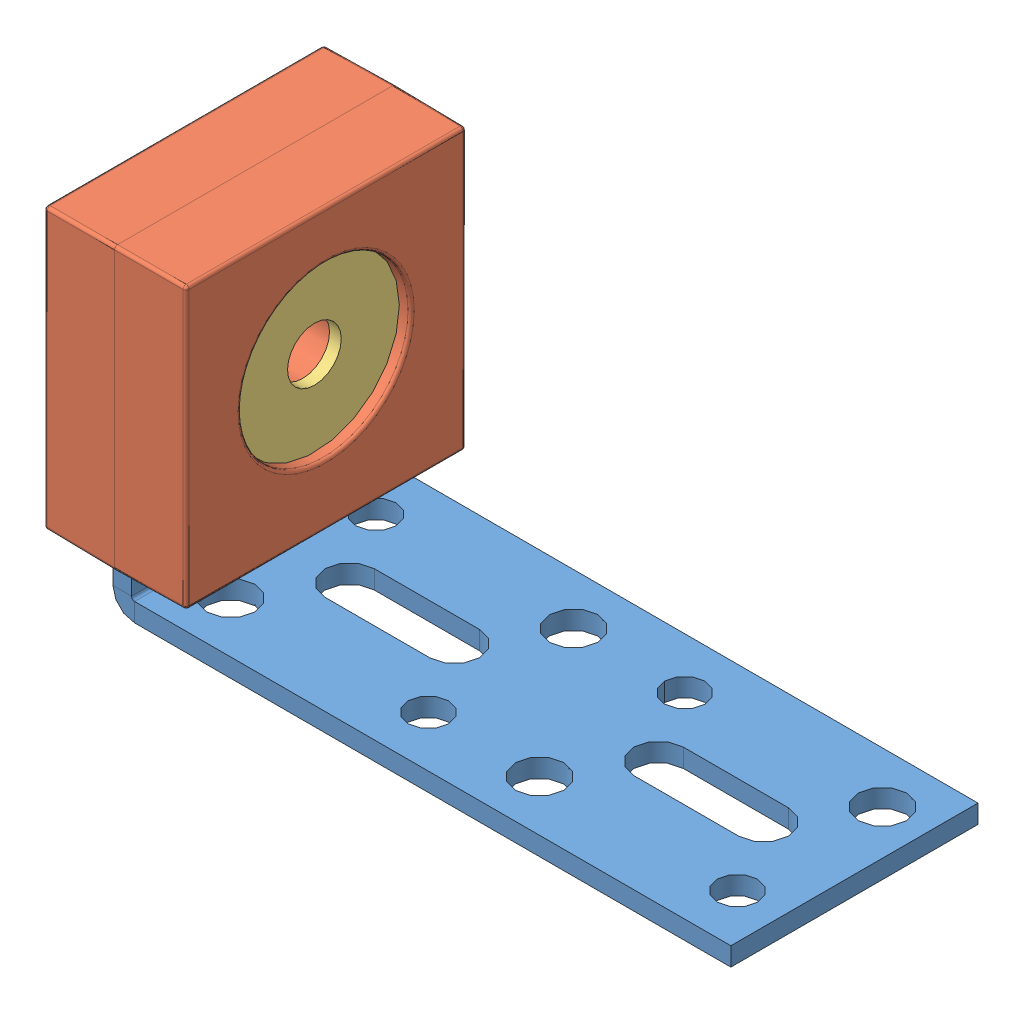
SolidWorks assembly 993684, configuration Default. Lengths in mm.
Overall size (108.5 53.9 45.5).
3 component instances, 3 part files, 5 mates.
Components (placement in the parent):
- 993684-1: 993684 [Default] at (-7.2845 29.1237 72.5984) size (100 50 40)
- 注塑-1: 注塑 [Default] at (-4.2845 60.0965 72.5984) size (23 45.5 45.5)
- 圆铁片-1: 圆铁片 [Default] at (3.4155 61.3237 72.5984) x (0 -1 0) z (0 0 1) size (30 1.9 30)
Mates (geometry in assembly coordinates):
- 重合1: coincident anti-aligned: plane of 993684-1 through (-3.7845 32.1237 92.5984) normal (0 0 1); plane of 注塑-1 through (-7.2845 79.1237 92.5984) normal (0 0 -1)
- 重合2: coincident anti-aligned: plane of 993684-1 through (-4.2845 79.1237 92.5984) normal (1 0 0); plane of 注塑-1 through (-4.2845 60.0965 72.5984) normal (-1 0 0)
- 同心1: concentric anti-aligned: cylinder of 993684-1 through (-14.2845 61.3237 72.5984) axis (1 0 0) radius 7.25; cone of 注塑-1 through (-4.2845 61.3237 72.5984) axis (-1 0 0)
- 重合3: coincident anti-aligned: plane of 注塑-1 through (3.4155 61.3237 72.5984) normal (1 0 0); plane of 圆铁片-1 through (3.4155 61.3237 72.5984) normal (-1 0 0)
- 同心2: concentric aligned: cone of 注塑-1 through (-4.2845 61.3237 72.5984) axis (-1 0 0); cylinder of 圆铁片-1 through (5.3155 61.3237 72.5984) axis (-1 0 0) radius 4.35
